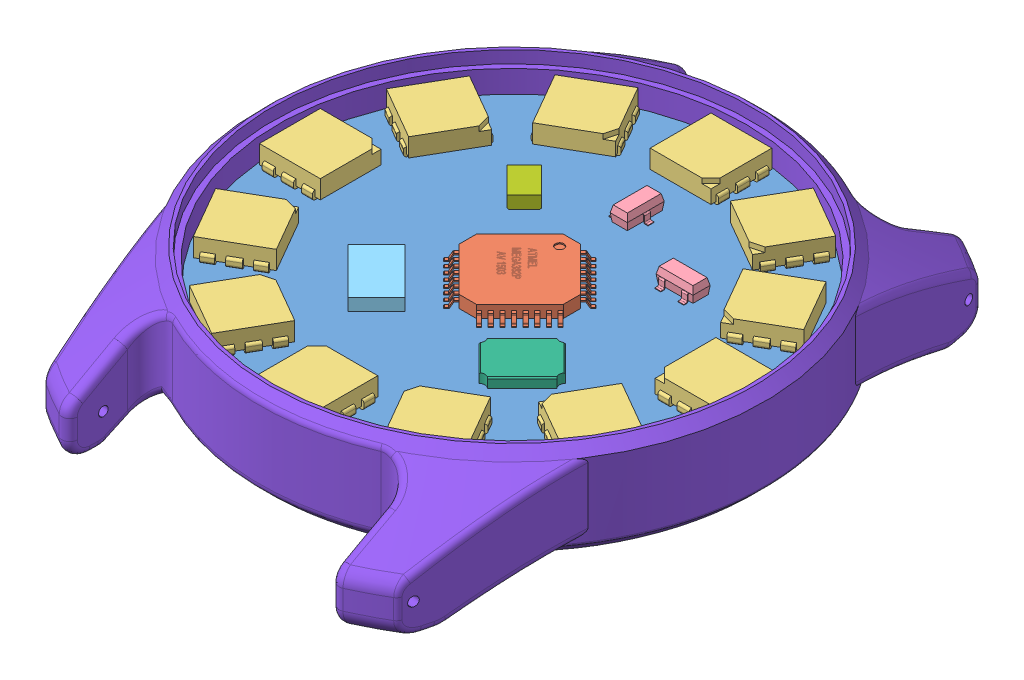
SolidWorks assembly watch board assembly, configuration Default. Lengths in mm.
Overall size (42.55 9.4 50.56).
20 component instances, 8 part files, 21 mates.
Components (placement in the parent):
- circiut board-1: circiut board [Default] at (34.4984 -9.6277 -15.8163) size (38 0.6 38)
- ATMEGA328P-1: ATMEGA328P [Predeterminado] at (29.7737 -9.0277 -16.2293) x (0.707107 0 0.707107) z (0 1 0) size (8.81 8.81 1.03)
- LED - SMD RGB (WS2812)-1: LED - SMD RGB (WS2812) [Default] at (18.4466 -8.8277 -16.2634) x (1 0 0) z (0 1 0) size (4.95 5.35 1.7)
- LED - SMD RGB (WS2812)-2: LED - SMD RGB (WS2812) [Default] at (42.319 -8.8277 -1.9597) x (-0.5 0 -0.866025) z (0 1 0) size (4.95 5.35 1.7)
- LED - SMD RGB (WS2812)-3: LED - SMD RGB (WS2812) [Default] at (26.5272 -8.8277 -29.7553) x (0.5 0 0.866025) z (0 1 0) size (4.95 5.35 1.7)
- LED - SMD RGB (WS2812)-4: LED - SMD RGB (WS2812) [Default] at (34.6666 -8.8277 -31.8429) x (0 0 1) z (0 1 0) size (4.95 5.35 1.7)
- LED - SMD RGB (WS2812)-5: LED - SMD RGB (WS2812) [Default] at (50.692 -8.8277 -16.2189) x (-1 0 0) z (0 1 0) size (4.95 5.35 1.7)
- LED - SMD RGB (WS2812)-6: LED - SMD RGB (WS2812) [Default] at (34.6695 -8.8277 0.2294) x (0 0 -1) z (0 1 0) size (4.95 5.35 1.7)
- LED - SMD RGB (WS2812)-7: LED - SMD RGB (WS2812) [Default] at (48.5245 -8.8277 -8.2528) x (-0.866025 0 -0.5) z (0 1 0) size (4.95 5.35 1.7)
- LED - SMD RGB (WS2812)-8: LED - SMD RGB (WS2812) [Default] at (20.6563 -8.8277 -23.7215) x (0.866025 0 0.5) z (0 1 0) size (4.95 5.35 1.7)
- LED - SMD RGB (WS2812)-9: LED - SMD RGB (WS2812) [Default] at (26.5007 -8.8277 -1.8468) x (0.5 0 -0.866025) z (0 1 0) size (4.95 5.35 1.7)
- LED - SMD RGB (WS2812)-10: LED - SMD RGB (WS2812) [Default] at (42.554 -8.8277 -29.814) x (-0.5 0 0.866025) z (0 1 0) size (4.95 5.35 1.7)
- LED - SMD RGB (WS2812)-11: LED - SMD RGB (WS2812) [Default] at (47.8535 -8.8277 -23.7323) x (-0.866025 0 0.5) z (0 1 0) size (4.95 5.35 1.7)
- LED - SMD RGB (WS2812)-12: LED - SMD RGB (WS2812) [Default] at (20.7353 -8.8277 -7.9313) x (0.866025 0 -0.5) z (0 1 0) size (4.95 5.35 1.7)
- SOT23-1: SOT23 [Predeterminado] at (41.7552 -8.3777 -22.4876) x (1 0 0) z (0 1 0) size (3 2.25 1.22)
- SOT23-2: SOT23 [Predeterminado] at (34.7637 -8.3777 -25.7387) x (0 0 1) z (0 1 0) size (3 2.25 1.22)
- adxl345-1: adxl345 [Default] at (29.0058 -9.0277 -10.2762) x (0.707107 0 -0.707107) z (0.707107 0 0.707107) size (3.3 1 5.3)
- crystal-1: crystal [Default] at (40.8043 -9.0277 -10.3406) x (-0.707107 0 -0.707107) z (0.707107 0 -0.707107) size (4 0.75 5)
- ds1308-1: ds1308 [Default] at (28.6281 -9.0277 -22.691) x (-0.707107 0 -0.707107) z (0.707107 0 -0.707107) size (3 1 2)
- watch with lip for 37mm board-1: watch with lip for 37mm board [Default] at (34.4984 -15.5199 -15.8163) x (0.030183 0 -0.999544) z (0.999544 0 0.030183) size (49.34 9.4 41.08)
Mates (geometry in assembly coordinates):
- Coincident1: coincident anti-aligned: plane of circiut board-1 through (34.4984 -9.0277 -15.8163) normal (0 1 0); plane of ATMEGA328P-1 through (29.7737 -9.0277 -16.2293) normal (0 -1 0)
- Coincident2: coincident anti-aligned: plane of circiut board-1 through (34.4984 -9.0277 -15.8163) normal (0 1 0); plane of ATMEGA328P-1 through (29.7737 -9.0277 -16.2293) normal (0 -1 0)
- Coincident3: coincident anti-aligned: plane of circiut board-1 through (34.4984 -9.0277 -15.8163) normal (0 1 0); plane of LED - SMD RGB (WS2812)-1 through (17.9466 -9.0277 -13.7884) normal (0 -1 0)
- Coincident4: coincident anti-aligned: plane of circiut board-1 through (34.4984 -9.0277 -15.8163) normal (0 1 0); plane of LED - SMD RGB (WS2812)-7 through (48.5245 -9.0277 -8.2528) normal (0 -1 0)
- Coincident5: coincident anti-aligned: plane of circiut board-1 through (34.4984 -9.0277 -15.8163) normal (0 1 0); plane of LED - SMD RGB (WS2812)-3 through (26.5272 -9.0277 -29.7553) normal (0 -1 0)
- Coincident6: coincident anti-aligned: plane of circiut board-1 through (34.4984 -9.0277 -15.8163) normal (0 1 0); plane of LED - SMD RGB (WS2812)-4 through (34.6666 -9.0277 -31.8429) normal (0 -1 0)
- Coincident7: coincident anti-aligned: plane of circiut board-1 through (34.4984 -9.0277 -15.8163) normal (0 1 0); plane of LED - SMD RGB (WS2812)-2 through (42.319 -9.0277 -1.9597) normal (0 -1 0)
- Coincident8: coincident anti-aligned: plane of circiut board-1 through (34.4984 -9.0277 -15.8163) normal (0 1 0); plane of LED - SMD RGB (WS2812)-5 through (50.692 -9.0277 -16.2189) normal (0 -1 0)
- Coincident9: coincident anti-aligned: plane of circiut board-1 through (34.4984 -9.0277 -15.8163) normal (0 1 0); plane of LED - SMD RGB (WS2812)-8 through (20.6563 -9.0277 -23.7215) normal (0 -1 0)
- Coincident10: coincident anti-aligned: plane of circiut board-1 through (34.4984 -9.0277 -15.8163) normal (0 1 0); plane of LED - SMD RGB (WS2812)-10 through (42.554 -9.0277 -29.814) normal (0 -1 0)
- Coincident11: coincident anti-aligned: plane of circiut board-1 through (34.4984 -9.0277 -15.8163) normal (0 1 0); plane of LED - SMD RGB (WS2812)-6 through (34.6695 -9.0277 0.2294) normal (0 -1 0)
- Coincident12: coincident anti-aligned: plane of circiut board-1 through (34.4984 -9.0277 -15.8163) normal (0 1 0); plane of LED - SMD RGB (WS2812)-9 through (26.5007 -9.0277 -1.8468) normal (0 -1 0)
- Coincident13: coincident anti-aligned: plane of circiut board-1 through (34.4984 -9.0277 -15.8163) normal (0 1 0); plane of LED - SMD RGB (WS2812)-12 through (20.7353 -9.0277 -7.9313) normal (0 -1 0)
- Coincident14: coincident anti-aligned: plane of circiut board-1 through (34.4984 -9.0277 -15.8163) normal (0 1 0); plane of LED - SMD RGB (WS2812)-11 through (47.8535 -9.0277 -23.7323) normal (0 -1 0)
- Coincident15: coincident anti-aligned: plane of circiut board-1 through (34.4984 -9.0277 -15.8163) normal (0 1 0); plane of SOT23-1 through (41.7552 -9.0277 -22.4876) normal (0 -1 0)
- Coincident16: coincident anti-aligned: plane of circiut board-1 through (34.4984 -9.0277 -15.8163) normal (0 1 0); plane of SOT23-2 through (34.7637 -9.0277 -25.7387) normal (0 -1 0)
- Coincident17: coincident anti-aligned: plane of circiut board-1 through (34.4984 -9.0277 -15.8163) normal (0 1 0); plane of adxl345-1 through (29.0058 -9.0277 -10.2762) normal (0 -1 0)
- Coincident18: coincident anti-aligned: plane of circiut board-1 through (34.4984 -9.0277 -15.8163) normal (0 1 0); plane of crystal-1 through (40.8043 -9.0277 -10.3406) normal (0 -1 0)
- Coincident20: coincident anti-aligned: plane of circiut board-1 through (34.4984 -9.0277 -15.8163) normal (0 1 0); plane of ds1308-1 through (28.6281 -9.0277 -22.691) normal (0 -1 0)
- Concentric1: concentric anti-aligned: cylinder of circiut board-1 through (34.4984 -9.0277 -15.8163) axis (0 -1 0) radius 19; cylinder of watch with lip for 37mm board-1 through (34.4984 -7.2409 -15.8163) axis (0 1 0) radius 19.5
- Coincident21: coincident anti-aligned: plane of circiut board-1 through (34.4984 -9.6277 -15.8163) normal (0 -1 0); plane of watch with lip for 37mm board-1 through (34.4984 -9.6277 -15.8163) normal (0 1 0)
